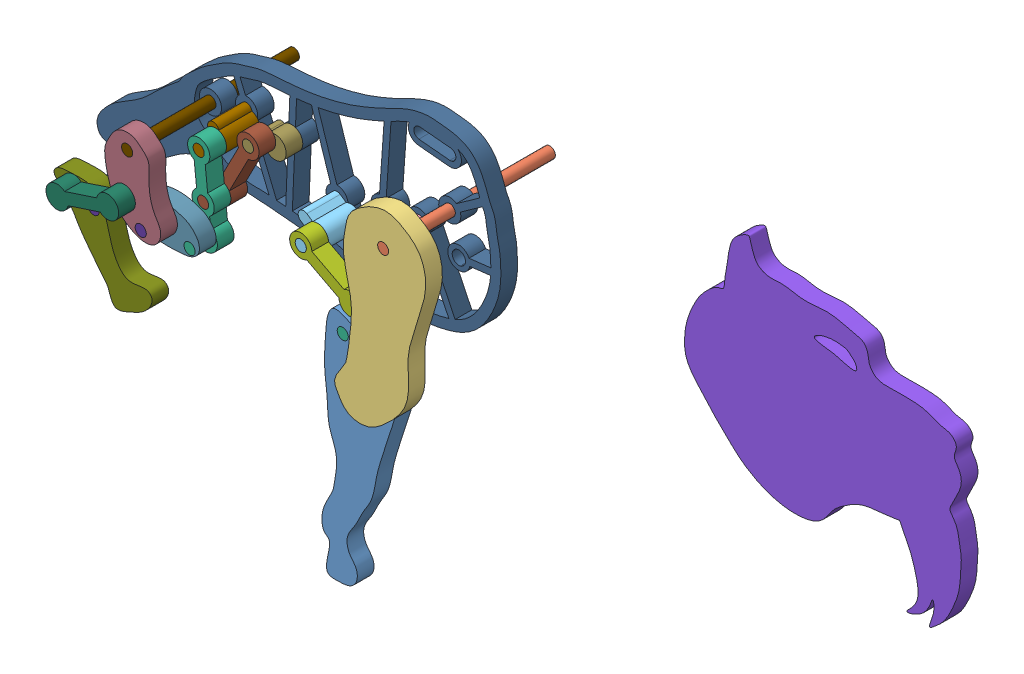
SolidWorks assembly Tiger, configuration Default. Lengths in mm.
Overall size (184.74 108.21 43.26).
20 component instances, 18 part files, 49 mates.
Components (placement in the parent):
- front leg bottom-1: front leg bottom [По умолчанию] at (-3.404 -25.0038 71.1812) x (0.997248 -0.074137 0) z (0 0 1) size (13.21 42.92 3)
- front legs axle-1: front legs axle [По умолчанию] at (1.1925 -2.9257 47.1812) x (0.793059 0.609145 0) z (0 0 1) size (2 2 30)
- front leg top-1: front leg top [По умолчанию] at (-2.614 -10.5274 74.1812) x (0.937742 0.347333 0) z (0 0 1) size (24.4 33.51 6)
- little link-2: little link [По умолчанию] at (-12.6822 -9.6276 68.1812) x (-0.507687 -0.861541 0) z (0 0 -1) size (6 4 9)
- little link 3-1: little link 3 [По умолчанию] at (-15.7439 -0.975 71.1812) x (0.823722 -0.566994 0) z (0 0 -1) size (6 4 12)
- front leg - link 1-1: front leg - link 1 [По умолчанию] at (-22.5903 -18.7668 71.1812) x (-0.238275 -0.971198 0) z (0 0 -1) size (17.2 4 6)
- back leg - little link 2-1: back leg - little link 2 [По умолчанию] at (-54.0343 -2.6959 74.1812) x (-0.885809 0.464049 0) z (0 0 -1) size (14 4 6)
- main head-1: main head [По умолчанию] at (81.9329 21.2814 87.4374) size (50.12 45.91 3)
- back leg - little link 3-3: back leg - little link 3 [По умолчанию] at (-32.6742 -1.9661 71.1812) x (0.222416 -0.974952 0) z (0 0 -1) size (4.8 4 12)
- front leg - link 1-2: front leg - link 1 [По умолчанию] at (-45.2739 -18.4114 74.1812) x (0.102726 -0.99471 0) z (0 0 -1) size (17.2 4 6)
- body-1: body [По умолчанию] at (-1.3804 51.2648 62.1812) x (0.981439 0.191773 0) z (0 0 1) size (74.4 31.95 3)
- 1-axle 1-hole-1: 1-axle 1-hole [По умолчанию] at (-11.6912 21.5652 68.1812) x (0.460167 0.887832 0) z (0 0 1) size (15 4 6)
- 2-axle link-4: 2-axle link [По умолчанию] at (-28.9228 -3.8817 65.1812) x (0.937586 -0.347753 0) z (0 0 1) size (5 4 9)
- hip-2: hip [По умолчанию] at (-36.4942 -30.6325 77.1812) x (0.999236 0.039089 0) z (0 0 1) size (10.32 15.95 3)
- middle hip-1: middle hip [По умолчанию] at (-41.4679 -22.7497 74.1812) x (0.997836 -0.065751 0) z (0 0 1) size (20.04 8.43 3)
- 2-axle same side link-2: 2-axle same side link [По умолчанию] at (-81.1598 -30.9102 83.1812) x (-0.949837 -0.312744 0) z (0 0 -1) size (13.56 4 6)
- bottom-1: bottom [По умолчанию] at (-56.3729 4.7891 77.1812) x (0.776534 0.630075 0) z (0 0 1) size (8.97 21.62 3)
- 1-axle short-2: 1-axle short [По умолчанию] at (-54.3368 -21.9435 74.1812) x (1 0.000129 0) z (0 0 1) size (2 2 6)
- 1-axle short-3: 1-axle short [По умолчанию] at (-44.3685 -21.0081 74.1812) x (0.989865 0.142013 0) z (0 0 1) size (2 2 6)
- 1-axle-2: 1-axle [По умолчанию] at (-48.3255 -9.8181 50.1812) size (2 2 30)
Mates (geometry in assembly coordinates):
- Parallel1: parallel anti-aligned: plane of main-1 through (93.9982 21.8072 87.4374) normal (0 0 -1)
- Parallel2: parallel anti-aligned: plane of paw-1 through (-54.1457 -25.4355 71.1812) normal (0 0 -1)
- Parallel3: parallel anti-aligned: plane of hip-1 through (-13.6493 -8.4176 74.1812) normal (0 0 -1)
- Coincident3: coincident anti-aligned: plane of paw-1 through (-54.1457 -25.4355 74.1812) normal (0 0 1); plane of hip-1 through (-13.6493 -8.4176 74.1812) normal (0 0 -1)
- Concentric2: concentric anti-aligned: cylinder of paw-1 through (-25.5644 -10.9779 74.1812) axis (0 0 -1) radius 1; cylinder of hip-1 through (-25.5644 -10.9779 71.1812) axis (0 0 1) radius 1
- Concentric5: concentric anti-aligned: cylinder of 1-axle 2-hole link-1 through (-18.9556 -0.3887 74.0097) axis (0 0 -1) radius 1; cylinder of 1-axle 1-hole link-1 through (-18.9556 -0.3887 68.1812) axis (0 0 1) radius 1
- Concentric8: concentric anti-aligned: cylinder of 2-axle link-2 through (-10.8587 0.9909 65.1812) axis (0 0 1) radius 1; cylinder of body-1 through (-10.8587 0.9909 65.1812) axis (0 0 -1) radius 1
- Concentric13: concentric aligned: cylinder of hip-1 through (-5.2711 5.4894 77.1812) axis (0 0 -1) radius 1; cylinder of long axle-1 through (-5.2711 5.4894 77.1812) axis (0 0 -1) radius 1
- Coincident13: coincident aligned: plane of hip-1 through (-13.6493 -8.4176 77.1812) normal (0 0 1); plane of long axle-1 through (-5.2711 5.4894 77.1812) normal (0 0 1)
- Concentric14: concentric aligned: cylinder of body-1 through (-5.2711 5.4894 65.1812) axis (0 0 -1) radius 1; cylinder of long axle-1 through (-5.2711 5.4894 77.1812) axis (0 0 -1) radius 1
- Concentric16: concentric anti-aligned: cylinder of body-1 through (-41.8456 2.9515 65.1812) axis (0 0 -1) radius 1; cylinder of 2-axle link-3 through (-41.8456 2.9515 65.1812) axis (0 0 1) radius 1
- Coincident15: coincident aligned: plane of paw-1 through (-54.1457 -25.4355 74.1812) normal (0 0 1); plane of 1-axle 2-hole link-1 through (-23.6402 -3.2127 74.1812) normal (0 0 1)
- Concentric19: concentric anti-aligned: cylinder of 1-axle 2-hole link-1 through (-18.9556 -0.3887 74.0097) axis (0 0 -1) radius 1; cylinder of 1-axle 1-hole link-1 through (-18.9556 -0.3887 68.1812) axis (0 0 1) radius 1
- Coincident17: coincident aligned: plane of 1-axle 2-hole link-1 through (-31.7086 -1.2778 68.1812) normal (0 0 -1); plane of 1-axle 1-hole link-1 through (-18.9556 -0.3887 68.1812) normal (0 0 -1)
- Parallel4: parallel aligned: plane of 2-axle link-1 through (-28.2615 -4.0492 74.1812) normal (0 0 1); plane of 1-axle 1-hole link-1 through (-49.8531 -26.2975 74.1812) normal (0 0 1)
- Concentric20: concentric anti-aligned: cylinder of 2-axle link-1 through (-28.2615 -4.0492 74.1812) axis (0 0 -1) radius 1; cylinder of 1-axle 1-hole link-1 through (-28.2615 -4.0492 68.3528) axis (0 0 1) radius 1
- Coincident19: coincident aligned: plane of 2-axle link-1 through (-28.2615 -4.0492 74.1812) normal (0 0 1); plane of 1-axle 1-hole link-1 through (-49.8531 -26.2975 74.1812) normal (0 0 1)
- Concentric21: concentric anti-aligned: cylinder of 2-axle link-1 through (-25.5528 -2.7596 65.1812) axis (0 0 1) radius 1; cylinder of body-1 through (-25.5528 -2.7596 65.1812) axis (0 0 -1) radius 1
- Concentric23: concentric aligned: cylinder of 2-axle link-2 through (-12.3355 3.6022 71.1812) axis (0 0 -1) radius 1; cylinder of 1-axle 2-hole link-1 through (-12.3355 3.6022 74.0097) axis (0 0 -1) radius 1
- Concentric24: concentric aligned: cylinder of 2-axle link-3 through (-41.4453 1.1966 74.1812) axis (0 0 -1) radius 1; cylinder of 1-axle 2-hole link-2 through (-41.4453 1.1966 77.0097) axis (0 0 -1) radius 1
- Coincident20: coincident aligned: plane of 2-axle link-3 through (-41.4453 1.1966 74.1812) normal (0 0 1); plane of 1-axle 2-hole link-2 through (-45.2739 -18.4114 74.1812) normal (0 0 1)
- Concentric25: concentric aligned: cylinder of 1-axle 2-hole link-2 through (-40.6512 -6.4925 77.0097) axis (0 0 -1) radius 1; cylinder of 1-axle 1-hole-1 through (-40.6512 -6.4925 74.1812) axis (0 0 -1) radius 1
- Coincident21: coincident aligned: plane of 1-axle 2-hole link-2 through (-45.2739 -18.4114 74.1812) normal (0 0 1); plane of 1-axle 1-hole-1 through (-40.6512 -6.4925 74.1812) normal (0 0 1)
- Concentric26: concentric anti-aligned: cylinder of body-1 through (-33.7142 2.5781 65.1812) axis (0 0 -1) radius 1; cylinder of 2-axle link-4 through (-33.7142 2.5781 62.1812) axis (0 0 1) radius 1
- Coincident23: coincident aligned: plane of 1-axle 1-hole-1 through (-11.6912 21.5652 71.1812) normal (0 0 1); plane of 2-axle link-4 through (-35.5893 3.2736 71.1812) normal (0 0 1)
- Coincident25: coincident aligned: plane of 2-axle link-1 through (-25.5528 -2.7596 62.1812) normal (0 0 -1); plane of body-1 through (-1.3804 51.2648 62.1812) normal (0 0 -1)
- Coincident26: coincident aligned: plane of 2-axle link-3 through (-41.8456 2.9515 62.1812) normal (0 0 -1); plane of body-1 through (-1.3804 51.2648 62.1812) normal (0 0 -1)
- Coincident27: coincident aligned: plane of 2-axle link-2 through (-12.3355 3.6022 71.1812) normal (0 0 1); plane of 1-axle 2-hole link-1 through (-31.7086 -1.2778 71.1812) normal (0 0 1)
- Concentric28: concentric aligned: cylinder of 1-axle 1-hole-1 through (-35.5893 3.2736 74.0097) axis (0 0 -1) radius 1; cylinder of 2-axle link-4 through (-35.5893 3.2736 68.1812) axis (0 0 -1) radius 1
- Parallel5: parallel anti-aligned: cylinder of 2-axle link-1 through (-28.2615 -4.0492 74.1812) axis (0 0 -1) radius 1; cylinder of 1-axle 1-hole link-1 through (-28.2615 -4.0492 68.3528) axis (0 0 1) radius 1
- Parallel7: parallel aligned: cylinder of paw-1 through (-23.6402 -3.2127 74.1812) axis (0 0 -1) radius 1; cylinder of 1-axle 2-hole link-1 through (-23.6402 -3.2127 74.1812) axis (0 0 -1) radius 1
- Concentric33: concentric aligned: cylinder of paw-1 through (-23.6402 -3.2127 74.1812) axis (0 0 -1) radius 1; cylinder of 1-axle 2-hole link-1 through (-23.6402 -3.2127 74.1812) axis (0 0 -1) radius 1
- Coincident33: coincident aligned: plane of 1-axle 2-hole link-2 through (-40.0893 -11.9336 77.1812) normal (0 0 1); plane of middle hip-1 through (-38.3253 -11.2742 77.1812) normal (0 0 1)
- Concentric43: concentric aligned: cylinder of bottom-1 through (-54.3382 -11.3325 80.1812) axis (0 0 -1) radius 1; cylinder of 1-axle short-2 through (-54.3382 -11.3325 80.1812) axis (0 0 -1) radius 1
- Coincident37: coincident aligned: plane of bottom-1 through (-56.918 -15.4645 80.1812) normal (0 0 1); plane of 1-axle short-2 through (-54.3382 -11.3325 80.1812) normal (0 0 1)
- Coincident43: coincident aligned: plane of middle hip-1 through (-38.3253 -11.2742 74.1812) normal (0 0 -1); plane of 1-axle short-2 through (-54.3382 -11.3325 74.1812) normal (0 0 -1)
- Concentric50: concentric anti-aligned: cylinder of 2-axle same side link-2 through (-57.9212 -9.7822 77.1812) axis (0 0 1) radius 1; cylinder of bottom-1 through (-57.9212 -9.7822 80.1812) axis (0 0 -1) radius 1
- Coincident45: coincident aligned: plane of hip-2 through (-43.674 -11.6851 77.1812) normal (0 0 -1); plane of 2-axle same side link-2 through (-81.1598 -30.9102 77.1812) normal (0 0 -1)
- Concentric59: concentric anti-aligned: cylinder of middle hip-1 through (-29.4186 -11.4856 71.3528) axis (0 0 1) radius 1; cylinder of 1-axle short-3 through (-29.4186 -11.4856 71.8758) axis (0 0 -1) radius 1
- Coincident48: coincident aligned: plane of hip-2 through (-43.674 -11.6851 80.1812) normal (0 0 1); plane of 1-axle short-3 through (-45.8754 -10.5047 80.1812) normal (0 0 1)
- Coincident50: coincident aligned: plane of middle hip-1 through (-38.3253 -11.2742 74.1812) normal (0 0 -1); plane of 1-axle short-3 through (-45.8754 -10.5047 74.1812) normal (0 0 -1)
- Coincident51: coincident aligned: plane of hip-2 through (-43.674 -11.6851 80.1812) normal (0 0 1); plane of 1-axle-2 through (-48.3255 0.7928 80.1812) normal (0 0 1)
- Concentric63: concentric aligned: cylinder of body-1 through (-48.3255 0.7928 65.1812) axis (0 0 -1) radius 1; cylinder of 1-axle-2 through (-48.3255 0.7928 80.1812) axis (0 0 -1) radius 1
- Concentric64: concentric aligned: cylinder of hip-2 through (-48.3255 0.7928 80.1812) axis (0 0 -1) radius 1; cylinder of 1-axle-2 through (-48.3255 0.7928 80.1812) axis (0 0 -1) radius 1
- Concentric65: concentric anti-aligned: cylinder of hip-2 through (-48.8441 -6.7935 80.1812) axis (0 0 -1) radius 1; cylinder of 2-axle same side link-2 through (-48.8441 -6.7935 77.1812) axis (0 0 1) radius 1
- Concentric66: concentric aligned: cylinder of hip-2 through (-45.8754 -10.5047 80.1812) axis (0 0 -1) radius 1; cylinder of 1-axle short-3 through (-45.8754 -10.5047 80.1812) axis (0 0 -1) radius 1
- Concentric67: concentric aligned: cylinder of 1-axle 2-hole link-2 through (-40.0893 -11.9336 77.1812) axis (0 0 -1) radius 1; cylinder of middle hip-1 through (-40.0893 -11.9336 77.1812) axis (0 0 -1) radius 1
- Concentric68: concentric aligned: cylinder of middle hip-1 through (-54.3382 -11.3325 77.1812) axis (0 0 -1) radius 1; cylinder of 1-axle short-2 through (-54.3382 -11.3325 80.1812) axis (0 0 -1) radius 1
- Concentric69: concentric aligned: cylinder of middle hip-1 through (-45.8754 -10.5047 77.1812) axis (0 0 -1) radius 1; cylinder of 1-axle short-3 through (-45.8754 -10.5047 80.1812) axis (0 0 -1) radius 1
